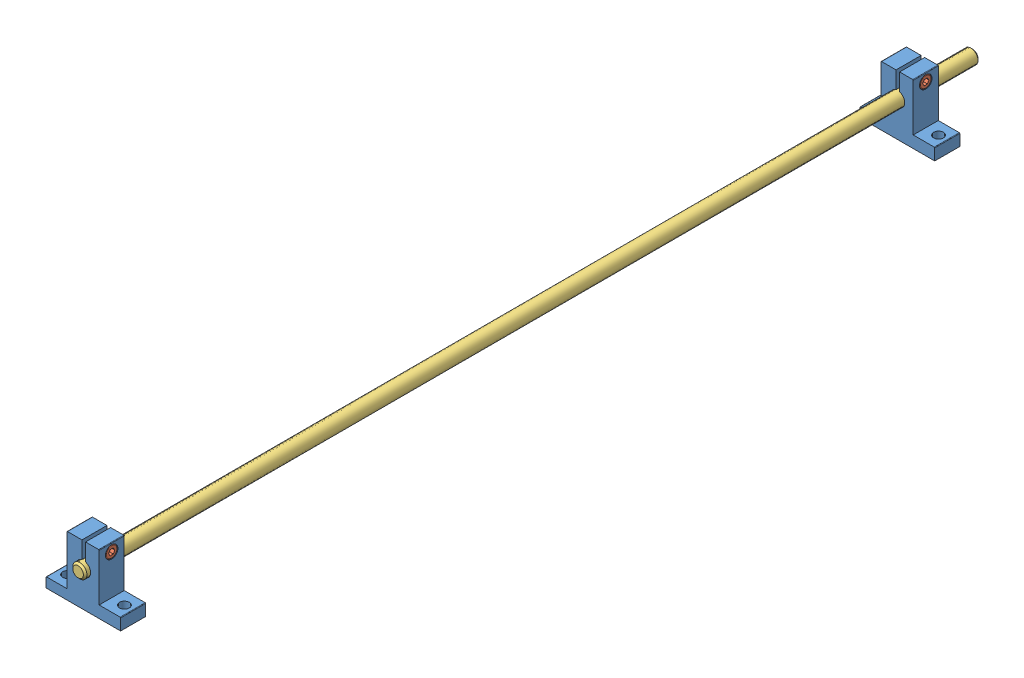
SolidWorks assembly Linear_Rod_Subassembly, configuration Default. Lengths in mm.
Overall size (41.7 33.3 500).
7 component instances, 3 part files, 5 mates.
Components (placement in the parent):
- SK8 Mount Assem-1: SK8 Mount Assem [Default] at origin size (41.7 33.3 14)
  - SK8 Mount-1: SK8 Mount [Default] at (17.5924 12.1999 37.4347) size (41.7 33.3 14)
  - 4mm x 12mm Allen Hex Nut-1: 4mm x 12mm Allen Hex Nut [Default] at (26.3535 36.2863 44.4347) x (0 0 1) z (-1 0 0) size (6.8 6.8 16.19)
- SK8 Mount Assem-4: SK8 Mount Assem [Default] at (0 0 455) size (41.7 33.3 14)
  - SK8 Mount-1: SK8 Mount [Default] at (17.5924 12.1999 37.4347) size (41.7 33.3 14)
  - 4mm x 12mm Allen Hex Nut-1: 4mm x 12mm Allen Hex Nut [Default] at (26.3535 36.2863 44.4347) x (0 0 1) z (-1 0 0) size (6.8 6.8 16.19)
- Linear_Rod_1-1: Linear_Rod_1 [Default] at (17.5924 27.2863 9.4347) x (-0.597029 0.80222 0) z (0 0 1) size (7.95 7.95 500)
Mates (geometry in assembly coordinates):
- Coincident2: coincident aligned: plane of SK8 Mount Assem-1/SK8 Mount-1 through (-3.3465 7.4863 51.4347) normal (0 -1 0); plane of SK8 Mount Assem-4/SK8 Mount-1 through (-3.3465 7.4863 506.4347) normal (0 -1 0)
- Concentric2: concentric aligned: cylinder of SK8 Mount Assem-1/SK8 Mount-1 through (17.5924 27.2863 51.4347) axis (0 0 -1) radius 4; cylinder of SK8 Mount Assem-4/SK8 Mount-1 through (17.5924 27.2863 506.4347) axis (0 0 -1) radius 4
- Concentric3: concentric aligned: cylinder of SK8 Mount Assem-4/SK8 Mount-1 through (17.5924 27.2863 506.4347) axis (0 0 -1) radius 4; cylinder of Linear_Rod_1-1 through (17.5924 27.2863 509.4347) axis (0 0 -1) radius 3.975
- Distance2: distance = 3 mm aligned: plane of SK8 Mount Assem-4/SK8 Mount-1 through (17.5924 12.1999 506.4347) normal (0 0 1); plane of Linear_Rod_1-1 through (17.5924 27.2863 509.4347) normal (0 0 1)
- Distance1: distance = 28 mm aligned: plane of SK8 Mount Assem-1/SK8 Mount-1 through (17.5924 12.1999 37.4347) normal (0 0 -1); plane of Linear_Rod_1-1 through (17.5924 27.2863 9.4347) normal (0 0 -1)
